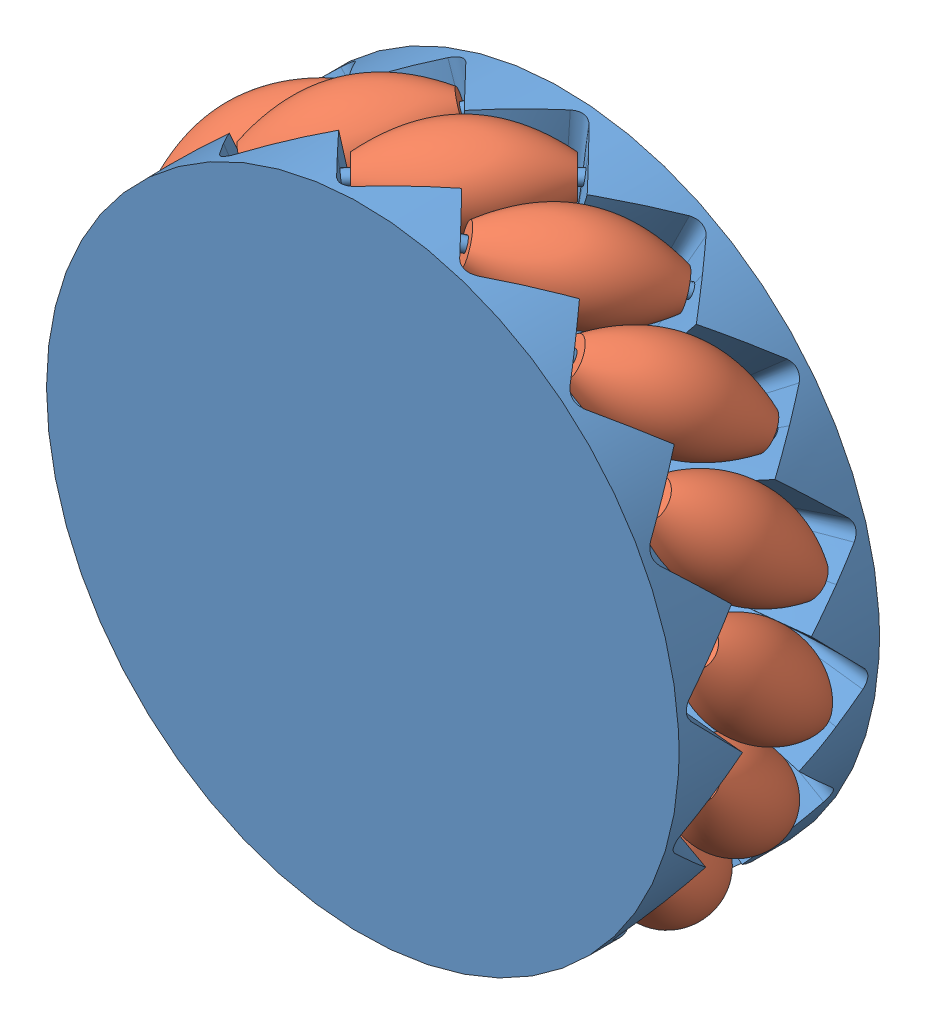
SolidWorks assembly 装配体2, configuration 默认. Lengths in mm.
Overall size (154.92 158.52 45).
17 component instances, 2 part files, 1 mates.
Components (placement in the parent):
- 麦克纳姆轮-1: 麦克纳姆轮 [默认] at (37.7684 81.9287 88.7194) size (142.16 158.52 45)
- 橡胶滚子-1: 橡胶滚子 [默认] at (75.6179 136.7142 97.2165) x (0.653281 -0.270598 -0.707107) z (0.680298 -0.200104 0.70509) size (36 20 20)
- 橡胶滚子-2: 橡胶滚子 [默认] at (51.7713 147.0283 97.2165) x (0.707107 0 -0.707107) z (0.70509 0.075467 0.70509) size (36 20 20)
- 橡胶滚子-3: 橡胶滚子 [默认] at (25.7928 147.4316 97.2165) x (0.653281 0.270598 -0.707107) z (0.622539 0.339549 0.70509) size (36 20 20)
- 橡胶滚子-4: 橡胶滚子 [默认] at (1.6376 137.8626 97.2165) x (0.5 0.5 -0.707107) z (0.445211 0.551937 0.70509) size (36 20 20)
- 橡胶滚子-5: 橡胶滚子 [默认] at (-17.0171 119.7782 97.2165) x (0.270598 0.653281 -0.707107) z (0.200104 0.680298 0.70509) size (36 20 20)
- 橡胶滚子-6: 橡胶滚子 [默认] at (-27.3312 95.9316 97.2165) x (0 0.707107 -0.707107) z (-0.075467 0.70509 0.70509) size (36 20 20)
- 橡胶滚子-7: 橡胶滚子 [默认] at (-27.7345 69.9532 97.2165) x (-0.270598 0.653281 -0.707107) z (-0.339549 0.622539 0.70509) size (36 20 20)
- 橡胶滚子-8: 橡胶滚子 [默认] at (-18.1655 45.7979 97.2165) x (-0.5 0.5 -0.707107) z (-0.551937 0.445211 0.70509) size (36 20 20)
- 橡胶滚子-9: 橡胶滚子 [默认] at (-0.0811 27.1432 97.2165) x (-0.653281 0.270598 -0.707107) z (-0.680298 0.200104 0.70509) size (36 20 20)
- 橡胶滚子-10: 橡胶滚子 [默认] at (23.7655 16.8292 97.2165) x (-0.707107 0 -0.707107) z (-0.70509 -0.075467 0.70509) size (36 20 20)
- 橡胶滚子-11: 橡胶滚子 [默认] at (49.7439 16.4259 97.2165) x (-0.653281 -0.270598 -0.707107) z (-0.622539 -0.339549 0.70509) size (36 20 20)
- 橡胶滚子-12: 橡胶滚子 [默认] at (73.8992 25.9949 97.2165) x (-0.5 -0.5 -0.707107) z (-0.445211 -0.551937 0.70509) size (36 20 20)
- 橡胶滚子-13: 橡胶滚子 [默认] at (92.5539 44.0792 97.2165) x (-0.270598 -0.653281 -0.707107) z (-0.200104 -0.680298 0.70509) size (36 20 20)
- 橡胶滚子-14: 橡胶滚子 [默认] at (102.868 67.9259 97.2165) x (0 -0.707107 -0.707107) z (0.075467 -0.70509 0.70509) size (36 20 20)
- 橡胶滚子-15: 橡胶滚子 [默认] at (103.2712 93.9043 97.2165) x (0.270598 -0.653281 -0.707107) z (0.339549 -0.622539 0.70509) size (36 20 20)
- 橡胶滚子-16: 橡胶滚子 [默认] at (93.7023 118.0596 97.2165) x (0.5 -0.5 -0.707107) z (0.551937 -0.445211 0.70509) size (36 20 20)
Mates (geometry in assembly coordinates):
- 同心1: concentric anti-aligned: cylinder of 麦克纳姆轮-1 through (79.013 135.308 93.5417) axis (-0.653281 0.270598 0.707107) radius 1.5; cylinder of 橡胶滚子-1 through (45.1374 149.3397 130.2084) axis (0.653281 -0.270598 -0.707107) radius 1.5
